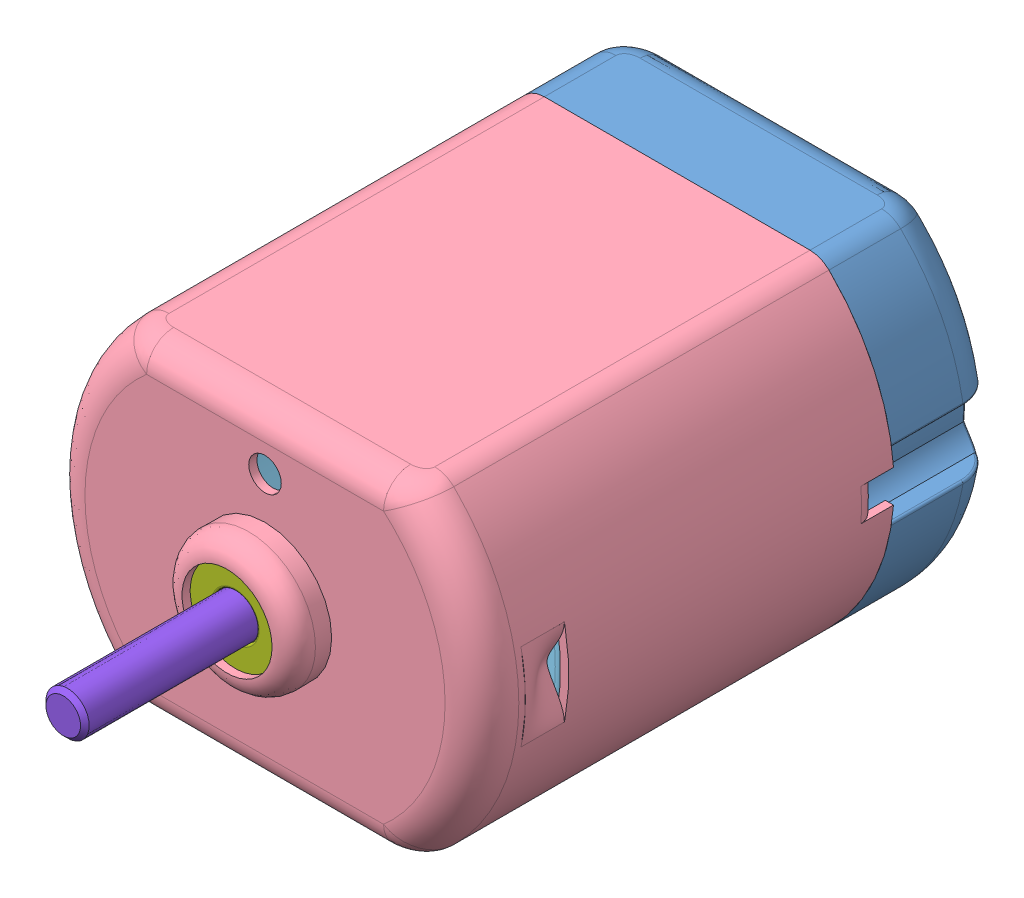
SolidWorks assembly Complete DC-Motor Assembly, configuration Default. Lengths in mm.
Overall size (20.01 18.13 38).
10 component instances, 8 part files, 19 mates.
Components (placement in the parent):
- DC Motor Cover-1: DC Motor Cover [Default] at origin size (19.93 15 10)
- Bearing 1-1: Bearing 1 [Default] at (0 0 -1) x (0.996254 0.086472 0) z (0 0 1) size (6 6 3)
- Brush-1: Brush [Default] at (-4.49 -2.335 4.9) x (-1 0 0) z (0 0 -1) size (7.84 5.94 7)
- Brush-2: Brush [Default] at (4.49 2.335 4.9) x (1 0 0) z (0 0 -1) size (7.84 5.94 7)
- DC Motor Case-1: DC Motor Case [Default] at (0 0 14.5) size (20.01 15 20.75)
- Magnet-1: Magnet [Default] at (-1.6142 -0.001 8) x (-1 -0.00062 0) z (0 0 1) size (4.99 13.78 12)
- Magnet-2: Magnet [Default] at (1.6142 -0.001 20) x (1 -0.00062 0) z (0 0 -1) size (4.99 13.78 12)
- Separator-1: Separator [Default] at (0.1985 -6.125 7.875) x (1 0 0) z (0 0 -1) size (9 1 15.75)
- Bearing 2-1: Bearing 2 [Default] at (0 0 25.375) x (-0.303258 -0.952909 0) z (0 0 -1) size (5.5 5.5 1.75)
- Rotor-1: Rotor [Default] at (0 0 14.3) x (0.778044 0.62821 0) z (0 0 1) size (13 12.8 38)
Mates (geometry in assembly coordinates):
- Concentric1: concentric anti-aligned: cylinder of DC Motor Cover-1 through (0 0 -1) axis (0 0 1) radius 3; cylinder of Bearing 1-1 through (0 0 2) axis (0 0 -1) radius 3
- Coincident1: coincident anti-aligned: plane of DC Motor Cover-1 through (0 0 -1) normal (0 0 1); plane of Bearing 1-1 through (0 0 -1) normal (0 0 -1)
- Coincident2: coincident anti-aligned: plane of DC Motor Cover-1 through (-5.6 -1.4 8) normal (1 0 0); plane of Brush-1 through (-5.6 -2.335 2.4) normal (-1 0 0)
- Width1: width aligned: plane of Brush-1 through (-5.6 1.335 -2.1) normal (0 1 0); plane of DC Motor Cover-1 through (-5.2 -1.335 2.4) normal (0 -1 0); plane of Brush-1 through (-5.6 -1.4 8) normal (0 1 0); plane of DC Motor Cover-1 through (-5.6 1.4 8) normal (0 -1 0)
- Concentric2: concentric aligned: cylinder of DC Motor Cover-1 through (0 0 6.5) axis (0 0 -1) radius 9.62; cylinder of DC Motor Case-1 through (0 0 24) axis (0 0 -1) radius 9.625
- Coincident3: coincident aligned: plane of DC Motor Cover-1 through (0 -7.5 5) normal (0 -1 0); plane of DC Motor Case-1 through (-6.6144 -7.5 24) normal (0 -1 0)
- Coincident4: coincident aligned: plane of DC Motor Cover-1 through (0 7.5 5) normal (0 1 0); plane of DC Motor Case-1 through (-6.6144 7.5 24) normal (0 1 0)
- Concentric3: concentric aligned: cylinder of DC Motor Case-1 through (0 0 24) axis (0 0 -1) radius 9.625; cylinder of Magnet-1 through (0 0 20) axis (0 0 -1) radius 9.63
- Coincident5: coincident anti-aligned: plane of DC Motor Case-1 through (-9.0241 0.1658 20) normal (0 0 -1); plane of Magnet-1 through (0 0 20) normal (0 0 1)
- Coincident7: coincident: line of DC Motor Case-1 through (-4.7918 -6.5266 14) axis (0 0 1); plane of Magnet-1 through (-4.8739 -6.883 20) normal (0.974509 -0.224347 0)
- Coincident8: coincident anti-aligned: plane of DC Motor Case-1 through (-6.6144 -7.125 24) normal (0 1 0); plane of Separator-1 through (-3.7515 -7.125 20.875) normal (0 -1 0)
- Coincident9: coincident anti-aligned: plane of DC Motor Case-1 through (0 0 23.625) normal (0 0 -1); plane of Separator-1 through (-1.7515 -6.125 23.625) normal (0 0 1)
- Width2: width aligned: plane of Separator-1 through (4.5015 -6.125 20.875) normal (1 0 0); plane of Magnet-2 through (-4.5015 -6.125 20.875) normal (-1 0 0); plane of Separator-1 through (4.8739 -6.883 8) normal (-0.974509 -0.224347 0); plane of Magnet-1 through (-4.8739 -6.883 20) normal (0.974509 -0.224347 0)
- Concentric4: concentric aligned: cylinder of DC Motor Case-1 through (0 0 25.75) axis (0 0 1) radius 2.075; cylinder of Bearing 2-1 through (0 0 23.625) axis (0 0 1) radius 2.75
- Coincident10: coincident aligned: circle of DC Motor Case-1; plane of Bearing 2-1 through (0 0 25.375) normal (0 0 1)
- Concentric5: concentric aligned: cylinder of Bearing 2-1 through (0 0 23.625) axis (0 0 1) radius 1; cylinder of Rotor-1 through (0 0 -4.7) axis (0 0 1) radius 1
- Coincident11: coincident anti-aligned: plane of Bearing 1-1 through (0 0 2) normal (0 0 1); plane of Rotor-1 through (-1.1282 -0.9109 2) normal (0 0 -1)
- Width3: width anti-aligned: plane of Brush-1 through (-3.12 -2.835 4.9) normal (0 0 1); plane of Rotor-1 through (-3.38 -2.835 2.4) normal (0 0 -1); plane of Brush-1 through (0 0 2.25) normal (0 0 -1); plane of Rotor-1 through (0.5189 -1.6375 5.05) normal (0 0 -1)
- Coincident12: coincident anti-aligned: plane of DC Motor Cover-1 through (0 0 5) normal (0 0 1); plane of DC Motor Case-1 through (0 0 5) normal (0 0 -1)
